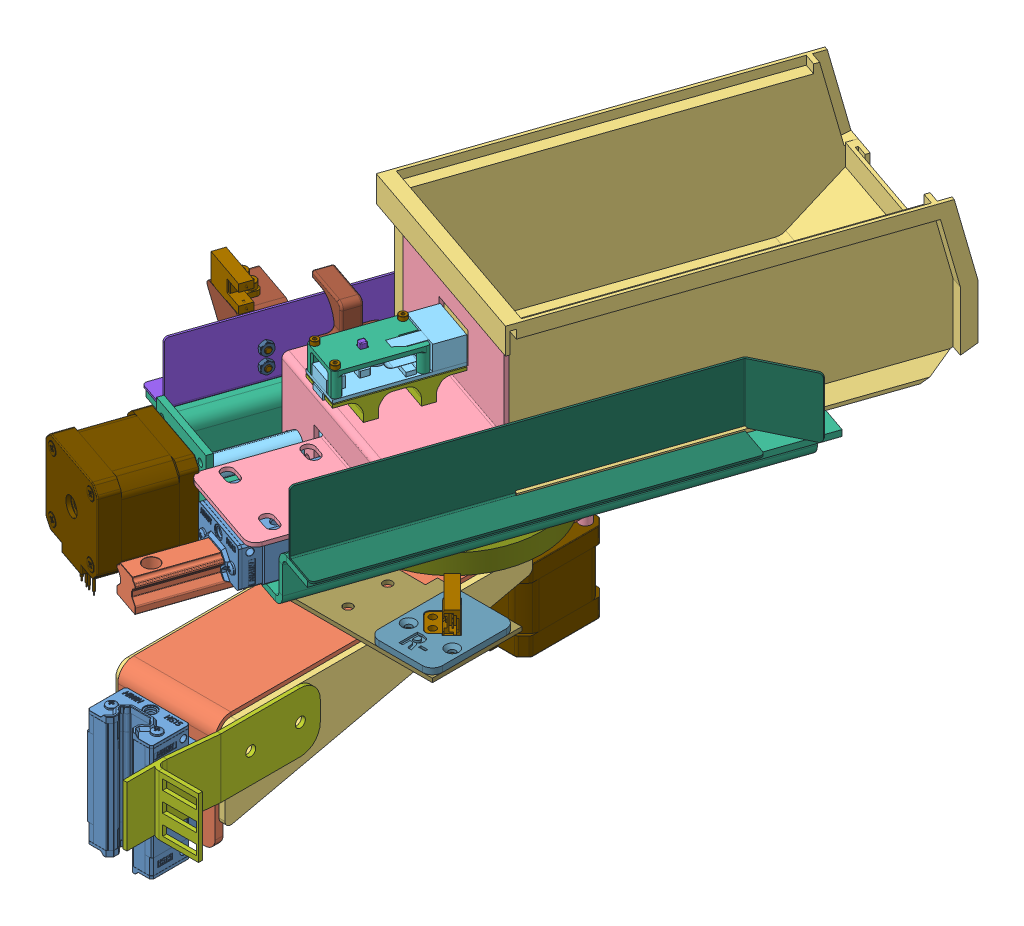
SolidWorks assembly T00003-000-R02, configuration Default. Lengths in mm.
Overall size (206.44 185.95 380.78).
59 component instances, 34 part files, 112 mates.
Components (placement in the parent):
- T00108-E00-R00-3: T00108-E00-R00 [Default] at (157.9488 862.2474 269.7743) x (1 0 0) z (0 1 0) size (34 23.7 61.49)
- T00110-E00-R00-1: T00110-E00-R00 [HGR15R400CE20] at (220.7447 918.7474 -18.1171) x (-0.945846 0 -0.324616) z (0.324616 0 -0.945846) size (15 15 270)
- T00108-E00-R00-4: T00108-E00-R00 [Default] at (154.4543 918.7474 175.0355) x (-0.945846 0 -0.324616) z (0.324616 0 -0.945846) size (34 23.7 61.49)
- T00148-E00-R00-1: T00148-E00-R00 [Default] at (206.0289 941.2474 119.0644) x (-0.945846 0 -0.324616) z (0.324616 0 -0.945846) size (104.77 76.2 187.32)
- T00006-000-R00-1: T00006-000-R00 [Default] at (104.8241 969.1581 159.4141) x (-0.945846 0 -0.324616) z (0 -1 0) size (100 103 92)
  - T00126-000-R02-1: T00126-000-R02 [Default] at (-76.7384 90.3354 70.4106) size (82 103 92)
  - T00005-000-R00-1: T00005-000-R00 [Default] at (-79.4687 62.4093 14.8739) x (0 -1 0) z (1 0 0) size (53.8 27.95 21.5)
    - T00154-E00-R01-1: T00154-E00-R01 [Default] at (15.674 22.2087 43.7303) size (53.8 16.25 21.5)
    - T00172-000-R01-1: T00172-000-R01 [Default] at (22.774 33.8087 43.7303) size (39 12 21.5)
    - T00171-000-R01-1: T00171-000-R01 [Default] at (15.674 10.2087 43.7303) size (53.2 12 21.5)
    - T00173-000-R01-1: T00173-000-R01 [Default] at (25.474 28.1587 43.0803) size (6 10 6)
    - socket head cap screw_iso-1: socket head cap screw_iso [ISO 4762 M2 x 16 - 16C] at (40.074 37.8087 51.9803) x (0 -1 0) z (0 0 1) size (18 3.8 3.8)
    - socket head cap screw_iso-4: socket head cap screw_iso [ISO 4762 M2 x 16 - 16C] at (5.074 37.8087 51.9803) x (0 -1 0) z (0 0 1) size (18 3.8 3.8)
    - socket head cap screw_iso-5: socket head cap screw_iso [ISO 4762 M2 x 16 - 16C] at (40.074 37.8087 35.4803) x (0 -1 0) z (0 0 1) size (18 3.8 3.8)
  - socket head cap screw_iso-1: socket head cap screw_iso [ISO 4762 M3 x 16 - 16C] at (-35.7384 58.3354 -6.3347) x (0 0 1) z (0 -1 0) size (19 5.5 5.5)
  - socket head cap screw_iso-2: socket head cap screw_iso [ISO 4762 M3 x 16 - 16C] at (-35.7384 35.3354 -6.3347) x (0 0 1) z (0 -1 0) size (19 5.5 5.5)
  - hex thin nut chamfered gradeab_iso-1: hex thin nut chamfered gradeab_iso [ISO - 4035 - M3 - C] at (-35.7384 35.3354 8.4653) size (5.5 6.35 1.8)
  - hex thin nut chamfered gradeab_iso-2: hex thin nut chamfered gradeab_iso [ISO - 4035 - M3 - C] at (-35.7384 58.3354 8.4653) size (5.5 6.35 1.8)
  - T00163-03D-R01-1: T00163-03D-R01 [Default] at (-4.7384 50.3354 4.6653) x (1 0 0) z (0 0 -1) size (38 30 18.2)
  - socket countersunk head screw_iso-1: socket countersunk head screw_iso [ISO 10642 - M3 x 8 - 8C] at (-9.7384 59.3354 1.6553) x (0 0 1) z (0.923728 0.383049 0) size (8 5.54 5.54)
  - socket countersunk head screw_iso-2: socket countersunk head screw_iso [ISO 10642 - M3 x 8 - 8C] at (-9.7384 41.3354 1.6553) x (0 0 1) z (0.923728 0.383049 0) size (8 5.54 5.54)
  - hex thin nut chamfered gradeab_iso-5: hex thin nut chamfered gradeab_iso [ISO - 4035 - M3 - C] at (-9.7384 41.3354 8.4653) size (5.5 6.35 1.8)
  - hex thin nut chamfered gradeab_iso-6: hex thin nut chamfered gradeab_iso [ISO - 4035 - M3 - C] at (-9.7384 59.3354 8.4653) size (5.5 6.35 1.8)
- T00127-E00-R00-1: T00127-E00-R00 [DIN 625 - 6002 - 12,SI,NC,12_68] at (157.9488 901.2474 97.7743) x (0 1 0) z (0 0 1) size (9 32 32)
- T00128-0A4-R00-1: T00128-0A4-R00 [Default] at (157.9488 887.7474 97.7743) x (1 0 0) z (0 -1 0) size (25 25 21)
- T00129-E00-R00-1: T00129-E00-R00 [Circlip DIN 471 - 15 x 1.5] at (157.9488 905.9474 97.7743) x (0.837169 0 0.546944) z (0 -1 0) size (17.74 21.49 1.5)
- T00130-0A4-R01-1: T00130-0A4-R01 [Default] at (157.9488 895.7474 97.7743) x (0.324616 0 -0.945846) z (0 -1 0) size (90 90 20)
- T00132-E00-R00-4: T00132-E00-R00 [Metric - Spur gear 1M 60T 20PA 9FW ---S60N75H50L42N] at (157.9488 896.7474 97.7743) x (0 1 0) z (0 0 1) size (9 61.95 61.95)
- T00107-E00-R00-1: T00107-E00-R00 [Varsayılan] at (157.9488 879.7474 61.7743) x (-1 0 0) z (0 1 0) size (42 58.5 65.65)
- T00131-E00-R00-2: T00131-E00-R00 [Metric - Spur gear 1M 12T 20PA 8FW ---S12O10H14L5N] at (157.9488 896.7474 61.7743) x (0 1 0) z (0.924225 0 0.381849) size (14 13.61 13.61)
- T00133-0A4-R00-3: T00133-0A4-R00 [Default] at (157.9488 862.2474 237.7743) x (1 0 0) z (0 1 0) size (49 210 57)
- T00134-DXF-R00-1: T00134-DXF-R00 [Default] at (130.4488 892.7474 239.7743) x (0 0 -1) z (-1 0 0) size (155 44.25 3)
- T00134-DXF-R00-2: T00134-DXF-R00 [Default] at (182.4488 892.7474 239.7743) x (0 0 -1) z (-1 0 0) size (155 44.25 3)
- T00105-E00-R00-1: T00105-E00-R00 [Default] at (142.4488 890.7474 46.2743) x (1 0 0) z (0 -1 0) size (6 6 11)
- T00105-E00-R00-2: T00105-E00-R00 [Default] at (173.4488 890.7474 46.2743) x (0.974973 0 -0.222324) z (0 -1 0) size (6 6 11)
- T00105-E00-R00-3: T00105-E00-R00 [Default] at (142.4488 890.7474 77.2743) x (1 0 0) z (0 -1 0) size (6 6 11)
- T00105-E00-R00-4: T00105-E00-R00 [Default] at (173.4488 890.7474 77.2743) x (1 0 0) z (0 -1 0) size (6 6 11)
- T00107-E00-R00-2: T00107-E00-R00 [Varsayılan] at (104.3679 933.2474 184.5821) x (0.945846 0 0.324616) z (0.324616 0 -0.945846) size (42 58.5 65.65)
- T00111-E00-R00-1: T00111-E00-R00 [Default] at (182.9251 933.2474 -44.3126) x (-0.536568 -0.823519 -0.184151) z (-0.778922 0.567289 -0.267328) size (10 240 10)
- T00135-DXF-R01-1: T00135-DXF-R01 [Default] at (162.818 918.7474 83.5866) x (-0.324616 0 0.945846) z (-0.945846 0 -0.324616) size (219 39 131)
- T00136-DXF-R01-1: T00136-DXF-R01 [Default] at (187.4488 877.7474 233.7743) x (0 0 -1) z (1 0 0) size (94.88 30 25)
- T00138-000-R00-1: T00138-000-R00 [gespiegeld] at (139.5613 941.2474 -4.2179) x (0.324616 0 -0.945846) z (0.945846 0 0.324616) size (201.93 32 21.92)
- T00153-E00-R00-4: T00153-E00-R00 [Default] at (89.0052 977.2474 133.8476) x (-0.324616 0 0.945846) z (0 1 0) size (13 22.4 13.7)
- socket head cap screw_iso-1: socket head cap screw_iso [ISO 4762 M3 x 16 - 16N] at (76.144 978.7474 122.0328) x (0 -1 0) z (0.992143 0 0.125105) size (19 5.5 5.5)
- hex nut style 1 gradeab_iso-1: hex nut style 1 gradeab_iso [ISO - 4032 - M3 - W - N] at (76.144 965.2474 122.0328) x (0.998096 0 0.061684) z (0 1 0) size (5.5 6.35 2.4)
- socket head cap screw_iso-2: socket head cap screw_iso [ISO 4762 M3 x 16 - 16N] at (82.7649 978.7474 124.3052) x (0 -1 0) z (-0.061684 0 0.998096) size (19 5.5 5.5)
- socket head cap screw_iso-3: socket head cap screw_iso [ISO 4762 M3 x 8 - 8N] at (86.5483 949.2474 125.6036) x (0.945846 0 0.324616) z (-0.316094 -0.227635 0.921014) size (11 5.5 5.5)
- socket head cap screw_iso-4: socket head cap screw_iso [ISO 4762 M3 x 8 - 8N] at (86.5483 957.2474 125.6036) x (0.945846 0 0.324616) z (-0.159414 -0.871112 0.46449) size (11 5.5 5.5)
- hex nut style 1 gradeab_iso-3: hex nut style 1 gradeab_iso [ISO - 4032 - M3 - W - N] at (82.7649 965.5626 124.3052) x (0.95019 0 0.311672) z (0 1 0) size (5.5 6.35 2.4)
- hex nut style 1 gradeab_iso-4: hex nut style 1 gradeab_iso [ISO - 4032 - M3 - W - N] at (94.115 957.2474 128.2005) x (0.159414 0.871112 -0.46449) z (-0.945846 0 -0.324616) size (5.5 6.35 2.4)
- hex nut style 1 gradeab_iso-5: hex nut style 1 gradeab_iso [ISO - 4032 - M3 - W - N] at (94.115 949.2474 128.2005) x (0.159414 0.871112 -0.46449) z (-0.945846 0 -0.324616) size (5.5 6.35 2.4)
- T00153-E00-R00-7: T00153-E00-R00 [Default] at (120.7549 900.9974 134.9681) x (0.707107 0 0.707107) z (0 1 0) size (13 22.4 13.7)
- T00153-E00-R00-8: T00153-E00-R00 [Default] at (195.1426 900.9974 134.9681) x (0.707107 0 -0.707107) z (0 1 0) size (13 22.4 13.7)
- T00168-03D-R00-2: T00168-03D-R00 [Default] at (93.1692 959.2474 127.8759) x (-0.324616 0 0.945846) z (-0.945846 0 -0.324616) size (20 28 25.65)
- T00161-0A4-R00-2: T00161-0A4-R00 [Default] at (157.9488 894.7474 147.7835) size (125 2 45)
- T00164-03D-R00-1: T00164-03D-R00 [Default] at (157.9488 896.7474 147.7835) x (1 0 0) z (0 1 0) size (32 42.2 3)
- T00165-03D-R00-1: T00165-03D-R00 [Default] at (250.9488 896.7474 147.7835) x (1 0 0) z (0 1 0) size (32 42.2 3)
- T00137-000-R00-2: T00137-000-R00 [gespiegeld] at (236.0376 941.2474 28.893) x (0.324616 0 -0.945846) z (0.945846 0 0.324616) size (201.93 32 21.92)
- T00162-03D-R03-1: T00162-03D-R03 [Default] at (174.1796 915.7474 50.482) x (-0.945846 0 -0.324616) z (0 -1 0) size (28 24.69 9)
Mates (geometry in assembly coordinates):
- Concentric8: concentric: cylinder of T00127-E00-R00-1 through (157.9488 880.6099 97.7743) axis (0 1 0) radius 7.5; cylinder of T00128-0A4-R00-1 through (157.9488 887.7474 97.7743) axis (0 -1 0) radius 7.5
- Coincident29: coincident: plane of T00127-E00-R00-1 through (147.8988 896.7474 97.7743) normal (0 -1 0); plane of T00128-0A4-R00-1 through (167.9488 896.7474 97.7743) normal (0 1 0)
- Concentric9: concentric: cylinder of T00128-0A4-R00-1 through (157.9488 887.7474 97.7743) axis (0 -1 0) radius 7.15; cylinder of T00129-E00-R00-1 through (157.9488 907.4474 97.7743) axis (0 -1 0) radius 7.15
- Coincident30: coincident: plane of T00128-0A4-R00-1 through (165.4488 905.9474 97.7743) normal (0 1 0); plane of T00129-E00-R00-1 through (157.9488 905.9474 97.7743) normal (0 -1 0)
- Concentric10: concentric: cylinder of T00127-E00-R00-1 through (157.9488 880.6099 97.7743) axis (0 1 0) radius 16; cylinder of T00130-0A4-R01-1 through (157.9488 895.7474 97.7743) axis (0 1 0) radius 16
- Coincident31: coincident: plane of T00127-E00-R00-1 through (142.2488 905.7474 97.7743) normal (0 1 0); plane of T00130-0A4-R01-1 through (163.1426 905.7474 82.6408) normal (0 -1 0)
- Concentric11: concentric: cylinder of T00130-0A4-R01-1 through (157.9488 895.7474 97.7743) axis (0 1 0) radius 21; cylinder of T00132-E00-R00-4 through (157.9488 946.7475 97.7743) axis (0 -1 0) radius 21
- Coincident32: coincident: plane of T00130-0A4-R01-1 through (164.7657 905.7474 77.9115) normal (0 -1 0); plane of T00132-E00-R00-4 through (157.9488 905.7474 97.7743) normal (0 1 0)
- Concentric12: concentric: cylinder of T00107-E00-R00-1 through (157.9488 904.7474 61.7743) axis (0 -1 0) radius 2.5; cylinder of T00131-E00-R00-2 through (157.9488 910.7475 61.7743) axis (0 -1 0) radius 2.5
- Coincident33: coincident: plane of T00107-E00-R00-1 through (159.9488 904.7474 61.7743) normal (0 1 0); plane of T00131-E00-R00-2 through (157.9488 904.7474 61.7743) normal (0 1 0)
- Distance5: distance = 1 mm: plane of T00131-E00-R00-2 through (157.9488 904.7474 61.7743) normal (0 1 0); plane of T00130-0A4-R01-1 through (164.7657 905.7474 77.9115) normal (0 -1 0)
- Coincident35: coincident: plane of T00128-0A4-R00-1 through (170.4488 890.7474 97.7743) normal (0 1 0); plane of T00133-0A4-R00-3 through (157.9488 890.7474 237.7743) normal (0 -1 0)
- Concentric15: concentric: cylinder of T00128-0A4-R00-1 through (157.9488 887.7474 97.7743) axis (0 -1 0) radius 12.5; cylinder of T00133-0A4-R00-3 through (157.9488 900.7474 97.7743) axis (0 -1 0) radius 10
- Concentric16: concentric: cone of T00107-E00-R00-1 through (142.4488 879.7474 46.2743) axis (0 -1 0); cylinder of T00133-0A4-R00-3 through (142.4488 894.7474 46.2743) axis (0 -1 0) radius 1.75
- Concentric17: concentric: circle of T00107-E00-R00-1; cylinder of T00133-0A4-R00-3 through (173.4488 894.7474 77.2743) axis (0 -1 0) radius 1.75
- Distance6: distance = 2 mm: plane of T00134-DXF-R00-2 through (185.4488 892.7474 233.7743) normal (0 1 0); plane of T00133-0A4-R00-3 through (157.9488 894.7474 237.7743) normal (0 1 0)
- Distance7: distance = 2 mm: plane of T00133-0A4-R00-3 through (157.9488 862.2474 241.7743) normal (0 0 1); plane of T00134-DXF-R00-2 through (185.4488 851.5004 239.7743) normal (0 0 1)
- Coincident39: coincident: plane of T00133-0A4-R00-3 through (182.4488 894.7474 31.7743) normal (1 0 0); plane of T00134-DXF-R00-2 through (182.4488 886.7474 233.7743) normal (-1 0 0)
- Coincident40: coincident: plane of T00133-0A4-R00-3 through (133.4488 894.7474 237.7743) normal (-1 0 0); plane of T00134-DXF-R00-1 through (133.4488 886.7474 233.7743) normal (1 0 0)
- Distance8: distance = 2 mm: plane of T00134-DXF-R00-1 through (133.4488 851.5004 239.7743) normal (0 0 1); plane of T00133-0A4-R00-3 through (157.9488 862.2474 241.7743) normal (0 0 1)
- Distance9: distance = 2 mm: plane of T00133-0A4-R00-3 through (157.9488 894.7474 237.7743) normal (0 1 0); plane of T00134-DXF-R00-1 through (133.4488 892.7474 233.7743) normal (0 1 0)
- Concentric18: concentric: cylinder of T00133-0A4-R00-3 through (173.4488 894.7474 46.2743) axis (0 -1 0) radius 1.75; cylinder of T00105-E00-R00-2 through (173.4488 879.7474 46.2743) axis (0 1 0) radius 1.75
- Coincident43: coincident: plane of T00107-E00-R00-1 through (157.9488 879.7474 61.7743) normal (0 1 0); plane of T00105-E00-R00-2 through (173.4488 879.7474 46.2743) normal (0 -1 0)
- Coincident44: coincident: plane of T00133-0A4-R00-3 through (157.9488 890.7474 237.7743) normal (0 -1 0); plane of T00105-E00-R00-1 through (142.4488 890.7474 46.2743) normal (0 1 0)
- Concentric19: concentric: cylinder of T00133-0A4-R00-3 through (142.4488 894.7474 46.2743) axis (0 -1 0) radius 1.75; cylinder of T00105-E00-R00-1 through (142.4488 879.7474 46.2743) axis (0 1 0) radius 1.75
- Coincident45: coincident: plane of T00133-0A4-R00-3 through (157.9488 890.7474 237.7743) normal (0 -1 0); plane of T00105-E00-R00-3 through (142.4488 890.7474 77.2743) normal (0 1 0)
- Concentric20: concentric: cylinder of T00133-0A4-R00-3 through (142.4488 894.7474 77.2743) axis (0 -1 0) radius 1.75; cylinder of T00105-E00-R00-3 through (142.4488 879.7474 77.2743) axis (0 1 0) radius 1.75
- Coincident46: coincident: plane of T00133-0A4-R00-3 through (157.9488 890.7474 237.7743) normal (0 -1 0); plane of T00105-E00-R00-4 through (173.4488 890.7474 77.2743) normal (0 1 0)
- Concentric21: concentric: cylinder of T00133-0A4-R00-3 through (173.4488 894.7474 77.2743) axis (0 -1 0) radius 1.75; cylinder of T00105-E00-R00-4 through (173.4488 879.7474 77.2743) axis (0 1 0) radius 1.75
- Coincident49: coincident: plane of T00110-E00-R00-1 through (126.9503 921.8332 235.1512) normal (-0.324616 0 0.945846); plane of T00107-E00-R00-2 through (91.221 933.2474 222.8888) normal (-0.324616 0 0.945846)
- Concentric22: concentric: cylinder of T00107-E00-R00-2 through (112.4833 933.2474 160.9359) axis (-0.324616 0 0.945846) radius 2.5; cylinder of T00111-E00-R00-1 through (114.7556 933.2474 154.315) axis (-0.324616 0 0.945846) radius 2.5
- Coincident51: coincident: plane of T00107-E00-R00-2 through (105.0171 933.2474 182.6904) normal (0.324616 0 -0.945846); plane of T00111-E00-R00-1 through (105.0171 933.2474 182.6904) normal (-0.324616 0 0.945846)
- Coincident52: coincident: plane of T00130-0A4-R01-1 through (172.5565 915.7474 55.2112) normal (0 1 0); plane of T00135-DXF-R01-1 through (162.818 915.7474 83.5866) normal (0 -1 0)
- Coincident53: coincident: plane of T00110-E00-R00-1 through (139.7192 918.7474 239.5335) normal (0 -1 0); plane of T00135-DXF-R01-1 through (162.818 918.7474 83.5866) normal (0 1 0)
- Distance11: distance = 3 mm: plane of T00107-E00-R00-2 through (104.3679 933.2474 184.5821) normal (0.324616 0 -0.945846); plane of T00135-DXF-R01-1 through (126.6233 918.7474 189.0484) normal (-0.324616 0 0.945846)
- Concentric23: concentric: cylinder of T00107-E00-R00-2 through (89.7073 948.7474 179.5505) axis (0.324616 0 -0.945846) radius 1.25; cylinder of T00135-DXF-R01-1 through (161.7721 948.7474 -30.4272) axis (-0.324616 0 0.945846) radius 1.75
- Concentric24: concentric: cylinder of T00107-E00-R00-2 through (119.0285 948.7474 189.6136) axis (0.324616 0 -0.945846) radius 1.25; cylinder of T00135-DXF-R01-1 through (191.0933 948.7474 -20.3641) axis (-0.324616 0 0.945846) radius 1.75
- Coincident55: coincident: plane of T00148-E00-R00-1 through (266.8377 941.2474 -58.1162) normal (0 -1 0); plane of T00135-DXF-R01-1 through (162.818 941.2474 83.5866) normal (0 1 0)
- Width12: width: plane of T00148-E00-R00-1 through (112.5737 941.2474 86.9903) normal (-0.945846 0 -0.324616); plane of T00148-E00-R00-1 through (200.3832 941.2474 117.1267) normal (0.945846 0 0.324616); plane of T00135-DXF-R01-1 through (190.8485 941.2474 203.6899) normal (0.945846 0 0.324616); plane of T00135-DXF-R01-1 through (66.9427 941.2474 161.1651) normal (-0.945846 0 -0.324616)
- Coincident74: coincident: plane of T00130-0A4-R01-1 through (157.9488 895.7474 97.7743) normal (0.945846 0 0.324616); plane of T00135-DXF-R01-1 through (162.818 918.7474 83.5866) normal (-0.945846 0 -0.324616)
- Distance14: distance = 15 mm: plane of T00135-DXF-R01-1 through (162.818 918.7474 83.5866) normal (-0.324616 0 0.945846); plane of T00130-0A4-R01-1 through (157.9488 895.7474 97.7743) normal (0.324616 0 -0.945846)
- Coincident133: coincident: plane of T00134-DXF-R00-2 through (185.4488 892.7474 233.7743) normal (0 1 0); plane of T00136-DXF-R01-1 through (185.4488 892.7474 273.7743) normal (0 1 0)
- Coincident134: coincident: plane of T00134-DXF-R00-2 through (185.4488 886.7474 233.7743) normal (1 0 0); plane of T00136-DXF-R01-1 through (185.4488 877.7474 233.7743) normal (-1 0 0)
- Concentric63: concentric: cylinder of T00134-DXF-R00-2 through (175.4488 877.7474 203.7743) axis (1 0 0) radius 2.75; cylinder of T00136-DXF-R01-1 through (185.4488 877.7474 203.7743) axis (1 0 0) radius 2.5
- Coincident136: coincident: plane of T00110-E00-R00-1 through (139.7192 918.7474 239.5335) normal (0 -1 0); plane of T00135-DXF-R01-1 through (162.818 918.7474 83.5866) normal (0 1 0)
- Coincident140: coincident: plane of T00135-DXF-R01-1 through (162.818 941.2474 83.5866) normal (0 1 0); plane of T00138-000-R00-1 through (139.5613 941.2474 -4.2179) normal (0 -1 0)
- Distance36: distance = 3 mm: plane of T00135-DXF-R01-1 through (66.9427 941.2474 161.1651) normal (-0.945846 0 -0.324616); plane of T00138-000-R00-1 through (64.1052 941.2474 160.1913) normal (-0.945846 0 -0.324616)
- Distance37: distance = 32 mm: plane of T00138-000-R00-1 through (122.5361 941.2474 -10.061) normal (0.324616 0 -0.945846); plane of T00135-DXF-R01-1 through (135.7614 941.2474 -39.3542) normal (0.324616 0 -0.945846)
- Width17: width: plane of T00108-E00-R00-4 through (149.4683 925.1631 204.1961) normal (-0.945846 0 -0.324616); plane of T00108-E00-R00-4 through (140.4827 925.1631 201.1122) normal (0.945846 0 0.324616); plane of T00110-E00-R00-1 through (140.1921 919.2474 239.6959) normal (0.945846 0 0.324616); plane of T00110-E00-R00-1 through (126.0044 919.2474 234.8266) normal (-0.945846 0 -0.324616)
- Concentric81: concentric: circle of T00108-E00-R00-3; cylinder of T00133-0A4-R00-3 through (144.9488 875.2474 241.7743) axis (0 0 -1) radius 2
- Concentric82: concentric: circle of T00108-E00-R00-3; cylinder of T00133-0A4-R00-3 through (170.9488 849.2474 241.7743) axis (0 0 -1) radius 2
- Coincident144: coincident: plane of T00108-E00-R00-3 through (173.9488 881.9474 241.7743) normal (0 0 -1); plane of T00133-0A4-R00-3 through (157.9488 862.2474 241.7743) normal (0 0 1)
- InPlace1: in place: plane of ? through (178.9488 905.7474 97.7743) normal (0 -1 0); plane of ? through (0 905.7474 0) normal (0 -1 0); moOrthogonalPlaneRef_w of ? through (178.9488 905.7474 97.7743) normal (0 -1 0); plane of ? through (0 905.7474 0) normal (0 0 -1); plane of ? through (178.9488 905.7474 97.7743) normal (0 -1 0); plane of ? through (0 905.7474 0) normal (-1 0 0); plane of ? through (158.7579 905.7474 76.7899) normal (0 -1 0); unknown of ?
- Coincident153: coincident: plane of T00130-0A4-R01-1; plane of ?
- Coincident154: coincident: moOrthogonalPlaneRef_w of T00130-0A4-R01-1 through (157.9488 905.7474 97.7743) axis (0.999257 0 0.038532); plane of ? through (157.9488 905.7474 97.7743) normal (0.999257 0 0.038532)
- Coincident155: coincident: moOrthogonalPlaneRef_w of T00130-0A4-R01-1; plane of ? through (157.9488 905.7474 97.7743) normal (0.038532 0 -0.999257)
- Concentric84: concentric: cylinder of T00153-E00-R00-4 through (76.144 973.2474 122.0328) axis (0 1 0) radius 1.75; cylinder of socket head cap screw_iso-1 through (76.144 1010.4974 122.0328) axis (0 1 0) radius 1.5
- Coincident182: coincident: plane of T00153-E00-R00-4 through (70.9115 975.7474 130.8096) normal (0 1 0); plane of socket head cap screw_iso-1 through (76.488 975.7474 119.3044) normal (0 -1 0)
- Concentric85: concentric: cylinder of socket head cap screw_iso-1 through (76.144 1010.4974 122.0328) axis (0 1 0) radius 1.5; cylinder of hex nut style 1 gradeab_iso-1 through (76.144 962.8474 122.0328) axis (0 1 0) radius 1.25
- Coincident184: coincident: plane of T00153-E00-R00-4 through (70.9115 975.7474 130.8096) normal (0 1 0); plane of socket head cap screw_iso-2 through (85.5097 975.7474 124.4748) normal (0 -1 0)
- Concentric86: concentric: cylinder of T00153-E00-R00-4 through (82.7649 973.2474 124.3052) axis (0 1 0) radius 1.75; cylinder of socket head cap screw_iso-2 through (82.7649 1010.4974 124.3052) axis (0 1 0) radius 1.5
- Concentric87: concentric: cylinder of socket head cap screw_iso-2 through (82.7649 1010.4974 124.3052) axis (0 1 0) radius 1.5; cylinder of hex nut style 1 gradeab_iso-3 through (82.7649 963.1626 124.3052) axis (0 1 0) radius 1.25
- Coincident186: coincident: plane of T00168-03D-R00-2 through (75.9983 965.2474 165.5851) normal (-0.945846 0 -0.324616); plane of socket head cap screw_iso-4 through (88.6082 958.5979 128.8433) normal (0.945846 0 0.324616)
- Coincident187: coincident: plane of T00168-03D-R00-2 through (75.9983 965.2474 165.5851) normal (-0.945846 0 -0.324616); plane of socket head cap screw_iso-3 through (89.1826 951.9252 127.1696) normal (0.945846 0 0.324616)
- Concentric92: concentric: cylinder of socket head cap screw_iso-4 through (56.5177 957.2474 115.2971) axis (-0.945846 0 -0.324616) radius 1.5; cylinder of hex nut style 1 gradeab_iso-4 through (96.3851 957.2474 128.9796) axis (-0.945846 0 -0.324616) radius 1.25
- Concentric93: concentric: cylinder of socket head cap screw_iso-3 through (56.5177 949.2474 115.2971) axis (-0.945846 0 -0.324616) radius 1.5; circle of hex nut style 1 gradeab_iso-5
- Coincident192: coincident: plane of ? through (157.9488 901.7474 97.7743) normal (0 -1 0); plane of ? through (156.3947 901.7474 61.5746) normal (0 1 0)
- Concentric94: concentric: cylinder of ? through (159.413 901.7474 59.8025) axis (0 1 0) radius 2.25; cylinder of ? through (159.413 865.9974 59.8025) axis (0 -1 0) radius 2
- Width24: width: plane of ? through (157.9488 905.7474 97.7743) normal (0 1 0); plane of ? through (157.9488 902.2474 97.7743) normal (0 -1 0); plane of T00153-E00-R00-7 through (124.2905 906.9974 135.6752) normal (0 -1 0); plane of T00153-E00-R00-7 through (118.3508 900.9974 141.6149) normal (0 1 0)
- Symmetric3: symmetric: plane of T00153-E00-R00-7 through (114.1081 900.9974 137.3723) normal (-0.707107 0 -0.707107); plane of T00153-E00-R00-7 through (118.3508 900.9974 141.6149) normal (0.707107 0 0.707107); plane of assembly
- Distance47: distance = 52 mm: moEndPointRef_w of T00153-E00-R00-7; axis of T00128-0A4-R00-1 through (157.9488 905.9474 97.7743) axis (0 -1 0)
- Width25: width: plane of T00153-E00-R00-8 through (201.7894 900.9974 137.3723) normal (0 1 0); plane of T00153-E00-R00-8 through (195.8497 906.9974 131.4326) normal (0 -1 0); plane of ? through (157.9488 905.7474 97.7743) normal (0 1 0); plane of ? through (157.9488 902.2474 97.7743) normal (0 -1 0)
- Symmetric4: symmetric: plane of T00153-E00-R00-8 through (201.7894 900.9974 137.3723) normal (0.707107 0 -0.707107); plane of T00153-E00-R00-8 through (197.5467 900.9974 141.6149) normal (-0.707107 0 0.707107)
- Distance48: distance = 52 mm: moEndPointRef_w of T00153-E00-R00-8; axis of T00130-0A4-R01-1 through (157.9488 905.7474 97.7743) axis (0 1 0)
- Distance49: distance = 0.25 mm: plane of T00153-E00-R00-7 through (108.4513 897.2974 151.5144) normal (-0.707107 0 0.707107); plane of T00164-03D-R00-1 through (108.4513 899.7474 151.868) normal (0.707107 0 -0.707107)
- Concentric98: concentric: cylinder of ? through (169.4056 901.7474 60.1878) axis (0 1 0) radius 1.75; cylinder of ? through (169.4056 866.9974 60.1878) axis (0 -1 0) radius 1.5
- Coincident226: coincident: plane of ? through (157.9488 901.7474 97.7743) normal (0 -1 0); circle of ?
- Coincident229: coincident: plane of ? through (157.9488 901.7474 97.7743) normal (0 -1 0); plane of ? through (151.9866 901.7474 58.4286) normal (0 1 0)
- Concentric100: concentric: cylinder of ? through (149.4204 901.7474 59.4172) axis (0 1 0) radius 1.75; cylinder of ? through (149.4204 866.9974 59.4172) axis (0 -1 0) radius 1.5
- Coincident237: coincident: plane of T00153-E00-R00-4 through (70.9115 973.2474 130.8096) normal (0 -1 0); plane of T00168-03D-R00-2 through (69.9317 973.2474 109.3282) normal (0 1 0)
- Concentric113: concentric: cylinder of socket head cap screw_iso-1 through (76.144 1010.4974 122.0328) axis (0 1 0) radius 1.5; cylinder of T00168-03D-R00-2 through (76.144 963.2474 122.0328) axis (0 1 0) radius 1.9
- Concentric114: concentric: cylinder of socket head cap screw_iso-2 through (82.7649 1010.4974 124.3052) axis (0 1 0) radius 1.5; cylinder of T00168-03D-R00-2 through (82.7649 963.2474 124.3052) axis (0 1 0) radius 1.9
- Concentric115: concentric: cylinder of socket head cap screw_iso-4 through (56.5177 957.2474 115.2971) axis (-0.945846 0 -0.324616) radius 1.5; cylinder of T00168-03D-R00-2 through (93.1692 957.2474 127.8759) axis (-0.945846 0 -0.324616) radius 1.9
- Concentric116: concentric: cylinder of socket head cap screw_iso-3 through (56.5177 949.2474 115.2971) axis (-0.945846 0 -0.324616) radius 1.5; cylinder of T00168-03D-R00-2 through (93.1692 949.2474 127.8759) axis (-0.945846 0 -0.324616) radius 1.9
- Coincident243: coincident: plane of hex nut style 1 gradeab_iso-1 through (76.3399 965.2474 118.8635) normal (0 1 0); plane of T00168-03D-R00-2 through (75.9983 965.2474 165.5851) normal (0 -1 0)
- Coincident244: coincident: plane of T00133-0A4-R00-3 through (157.9488 894.7474 237.7743) normal (0 1 0); plane of T00161-0A4-R00-2 through (157.9488 894.7474 147.7835) normal (0 -1 0)
- Parallel3: parallel: line of T00133-0A4-R00-3 through (172.4488 890.7474 31.7743) axis (-1 0 0); line of T00161-0A4-R00-2 through (137.9488 894.7474 125.2835) axis (-1 0 0)
- Width26: width: plane of T00161-0A4-R00-2 through (220.4488 896.7474 170.2835) normal (1 0 0); plane of T00161-0A4-R00-2 through (95.4488 896.7474 170.2835) normal (-1 0 0); plane of T00134-DXF-R00-1 through (130.4488 886.7474 233.7743) normal (-1 0 0); plane of T00134-DXF-R00-2 through (185.4488 886.7474 233.7743) normal (1 0 0)
- Concentric117: concentric: cylinder of T00161-0A4-R00-2 through (100.4488 886.7474 155.2835) axis (0 1 0) radius 1.7; cylinder of T00164-03D-R00-1 through (100.4488 899.7474 155.2835) axis (0 1 0) radius 1.7
- Coincident245: coincident: plane of T00161-0A4-R00-2 through (157.9488 896.7474 147.7835) normal (0 1 0); plane of T00164-03D-R00-1 through (157.9488 896.7474 147.7835) normal (0 -1 0)
- Coincident246: coincident: plane of T00161-0A4-R00-2 through (95.4488 896.7474 170.2835) normal (0 0 1); line of T00164-03D-R00-1 through (100.4488 896.7474 170.2835) axis (1 0 0)
- Coincident247: coincident: plane of T00161-0A4-R00-2 through (157.9488 896.7474 147.7835) normal (0 1 0); plane of T00165-03D-R00-1 through (250.9488 896.7474 147.7835) normal (0 -1 0)
- Concentric118: concentric: cylinder of T00161-0A4-R00-2 through (215.4488 886.7474 155.2835) axis (0 1 0) radius 1.7; cylinder of T00165-03D-R00-1 through (215.4488 899.7474 155.2835) axis (0 1 0) radius 1.7
- Coincident248: coincident: plane of T00161-0A4-R00-2 through (95.4488 896.7474 170.2835) normal (0 0 1); line of T00165-03D-R00-1 through (193.4488 896.7474 170.2835) axis (1 0 0)
- Coincident249: coincident: plane of T00108-E00-R00-4 through (145.7157 946.7474 151.2085) normal (0 1 0); plane of T00006-000-R00-1/T00126-000-R02-1 through (206.7312 946.7474 98.8813) normal (0 -1 0)
- Concentric119: concentric: cylinder of T00110-E00-R00-1 through (126.7138 927.7474 235.0701) axis (0.324616 0 -0.945846) radius 1.6; cylinder of T00108-E00-R00-4 through (139.078 927.7474 199.0442) axis (0.324616 0 -0.945846) radius 1.5
- Width28: width: plane of T00006-000-R00-1/T00126-000-R02-1 through (131.3964 1012.4928 88.8851) normal (0.945846 0 0.324616); plane of T00006-000-R00-1/T00126-000-R02-1 through (141.8007 1012.4928 92.4559) normal (-0.945846 0 -0.324616); plane of T00107-E00-R00-2 through (81.9082 916.0474 185.3319) normal (-0.945846 0 -0.324616); plane of T00107-E00-R00-2 through (121.6337 950.4474 198.9658) normal (0.945846 0 0.324616)
- Width29: width: plane of T00006-000-R00-1/T00126-000-R02-1 through (173.6203 898.7474 195.3576) normal (-0.324616 0 0.945846); plane of T00006-000-R00-1/T00126-000-R02-1 through (182.0603 898.7474 170.7656) normal (0.324616 0 -0.945846); plane of T00108-E00-R00-4 through (135.8579 926.9474 189.4811) normal (-0.324616 0 0.945846); plane of T00108-E00-R00-4 through (148.6478 926.9474 152.2148) normal (0.324616 0 -0.945846)
- Width30: width: plane of T00108-E00-R00-4 through (138.8005 918.7474 169.6631) normal (-0.945846 0 -0.324616); plane of T00108-E00-R00-4 through (176.9286 924.0474 161.9208) normal (0.945846 0 0.324616); plane of T00006-000-R00-1/T00126-000-R02-1 through (160.3847 898.7474 82.9751) normal (-0.945846 0 -0.324616); plane of T00006-000-R00-1/T00126-000-R02-1 through (190.5004 948.7474 146.1736) normal (0.945846 0 0.324616)
- Coincident252: coincident: plane of T00148-E00-R00-1 through (207.4315 941.2474 114.9805) normal (-0.324616 0 0.945846); plane of T00006-000-R00-1/T00126-000-R02-1 through (201.8619 1012.4928 113.069) normal (0.324616 0 -0.945846)
- Coincident253: coincident: plane of T00138-000-R00-1 through (138.6155 941.2474 -4.5425) normal (-0.945846 0 -0.324616); plane of T00168-03D-R00-2 through (93.1692 959.2474 127.8759) normal (0.945846 0 0.324616)
- Coincident254: coincident: plane of T00138-000-R00-1 through (138.6155 973.2474 -4.5425) normal (0 1 0); plane of T00168-03D-R00-2 through (69.9317 973.2474 109.3282) normal (0 1 0)
- Coincident255: coincident: plane of T00138-000-R00-1 through (139.5613 941.2474 -4.2179) normal (0.945846 0 0.324616); plane of hex nut style 1 gradeab_iso-4 through (95.013 955.688 125.5842) normal (-0.945846 0 -0.324616)
- Coincident256: coincident: plane of T00138-000-R00-1 through (139.5613 941.2474 -4.2179) normal (0.945846 0 0.324616); plane of hex nut style 1 gradeab_iso-5 through (95.013 947.688 125.5842) normal (-0.945846 0 -0.324616)
- LimitDistance5: limit distance = 43.2885 mm: plane of T00006-000-R00-1/T00126-000-R02-1 through (185.6311 1012.4928 160.3613) normal (-0.324616 0 0.945846); plane of T00135-DXF-R01-1 through (127.5971 918.7474 186.2109) normal (0.324616 0 -0.945846)
- Distance52: distance = 30 mm: plane of T00168-03D-R00-2 through (63.4394 945.2474 128.2451) normal (-0.324616 0 0.945846); plane of T00138-000-R00-1 through (80.1846 941.2474 165.7098) normal (-0.324616 0 0.945846)
- Coincident257: coincident: plane of T00135-DXF-R01-1 through (162.818 941.2474 83.5866) normal (0 1 0); plane of T00137-000-R00-2 through (236.0376 941.2474 28.893) normal (0 -1 0)
- Distance53: distance = 3 mm: plane of T00137-000-R00-2 through (193.686 941.2474 204.6637) normal (0.945846 0 0.324616); plane of T00135-DXF-R01-1 through (190.8485 941.2474 203.6899) normal (0.945846 0 0.324616)
- Coincident259: coincident: plane of T00135-DXF-R01-1 through (171.9316 941.2474 197.1975) normal (-0.324616 0 0.945846); plane of T00137-000-R00-2 through (177.6067 941.2474 199.1452) normal (-0.324616 0 0.945846)
- Coincident260: coincident: plane of T00135-DXF-R01-1 through (162.818 915.7474 83.5866) normal (0 -1 0); plane of T00162-03D-R03-1 through (174.1796 915.7474 50.482) normal (0 1 0)
- Concentric121: concentric: cylinder of T00130-0A4-R01-1 through (157.9488 895.7474 97.7743) axis (0 1 0) radius 45; cylinder of T00162-03D-R03-1 through (157.9488 912.2474 97.7743) axis (0 1 0) radius 45
- Coincident262: coincident: plane of T00135-DXF-R01-1 through (162.818 918.7474 83.5866) normal (-0.945846 0 -0.324616); plane of T00162-03D-R03-1 through (174.1796 915.7474 50.482) normal (-0.945846 0 -0.324616)
